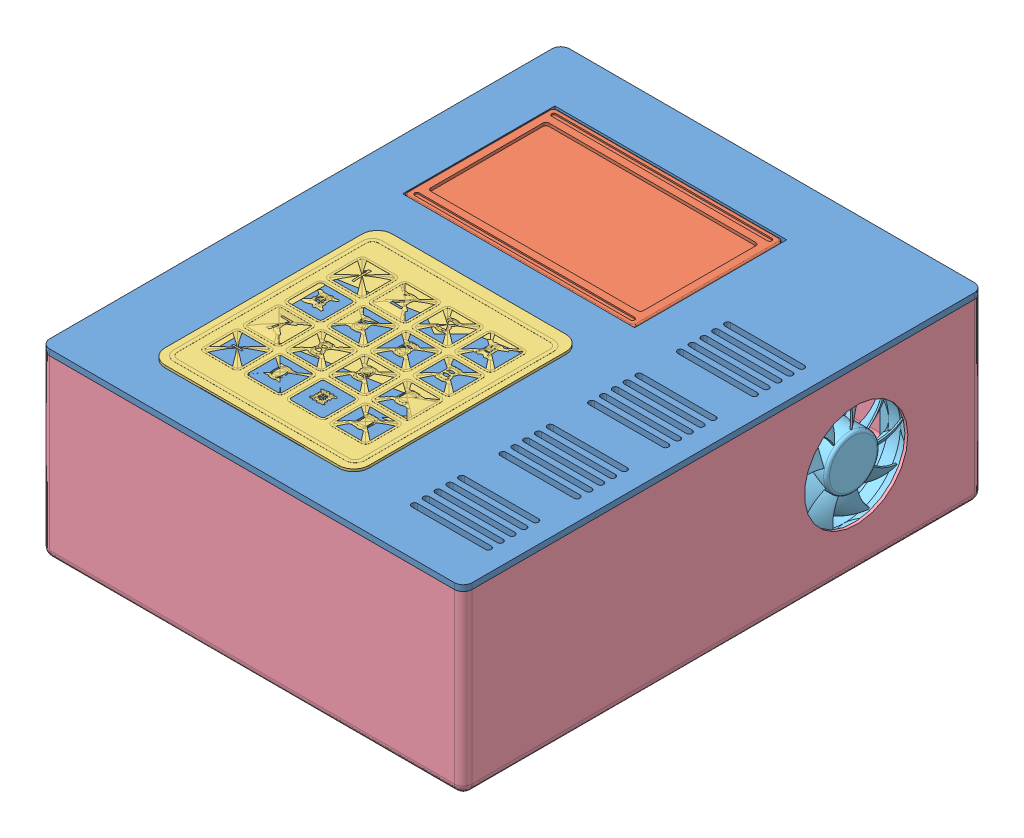
SolidWorks assembly Assembly1, configuration Default. Lengths in mm.
Overall size (143 63.49 176).
5 component instances, 5 part files, 12 mates.
Components (placement in the parent):
- MetalEncloser_3D_model-1: MetalEncloser_3D_model [Default] at (11.2892 67.9363 14.9726) size (143 2 176)
- Graphic LCD-1: Graphic LCD [Default] at (-35.4608 61.4363 -24.7774) size (93 13.16 70)
- Keypad-1: Keypad [Default] at (-34.2303 70.7491 53.5297) size (68.96 10.64 77.9)
- MetalEncloser_3d_model_bottom-1: MetalEncloser_3d_model_bottom [Default] at (-20.2108 7.9363 17.9726) size (143 60 176)
- 40mm_Fan-1: 40mm_Fan [Default] at (40.2892 39.4363 -27.0274) x (0 0 -1) z (1 0 0) size (41.57 42 10.33)
Mates (geometry in assembly coordinates):
- Tangent1: tangent: plane of MetalEncloser_3D_model-1 through (11.2892 69.9363 14.9726) normal (0 1 0); face of Graphic LCD-1
- Tangent2: tangent: plane of MetalEncloser_3D_model-1 through (-74.4608 69.9363 -50.7774) normal (1 0 0); face of Graphic LCD-1
- Tangent3: tangent: plane of MetalEncloser_3D_model-1 through (-74.4608 69.9363 0.7226) normal (0 0 -1); face of Graphic LCD-1
- Tangent4: tangent: plane of MetalEncloser_3D_model-1 through (11.2892 69.9363 14.9726) normal (0 1 0); face of Keypad-1
- Tangent5: tangent: plane of MetalEncloser_3D_model-1 through (-52.7108 69.9363 91.9726) normal (0 0 -1); face of Keypad-1
- Tangent6: tangent: plane of MetalEncloser_3D_model-1 through (-68.7108 69.8363 48.9726) normal (1 0 0); face of Keypad-1
- Coincident1: coincident: plane of MetalEncloser_3D_model-1 through (11.2892 67.9363 14.9726) normal (0 -1 0); plane of MetalEncloser_3d_model_bottom-1 through (-20.2108 67.9363 17.9726) normal (0 1 0)
- Coincident2: coincident: plane of MetalEncloser_3D_model-1 through (-91.7108 69.9363 -70.0274) normal (-1 0 0); plane of MetalEncloser_3d_model_bottom-1 through (-91.7108 67.9363 105.9726) normal (-1 0 0)
- Coincident3: coincident: plane of MetalEncloser_3D_model-1 through (-91.7108 69.9363 105.9726) normal (0 0 1); plane of MetalEncloser_3d_model_bottom-1 through (-91.7108 67.9363 105.9726) normal (0 0 1)
- Concentric1: concentric: circle of MetalEncloser_3d_model_bottom-1; circle of 40mm_Fan-1
- Parallel1: parallel: plane of MetalEncloser_3D_model-1 through (11.2892 69.9363 14.9726) normal (0 1 0); plane of 40mm_Fan-1 through (40.2892 59.4363 -47.0274) normal (0 1 0)
- Coincident7: coincident: circle of MetalEncloser_3d_model_bottom-1; plane of 40mm_Fan-1 through (50.2892 39.4363 -27.0274) normal (1 0 0)
